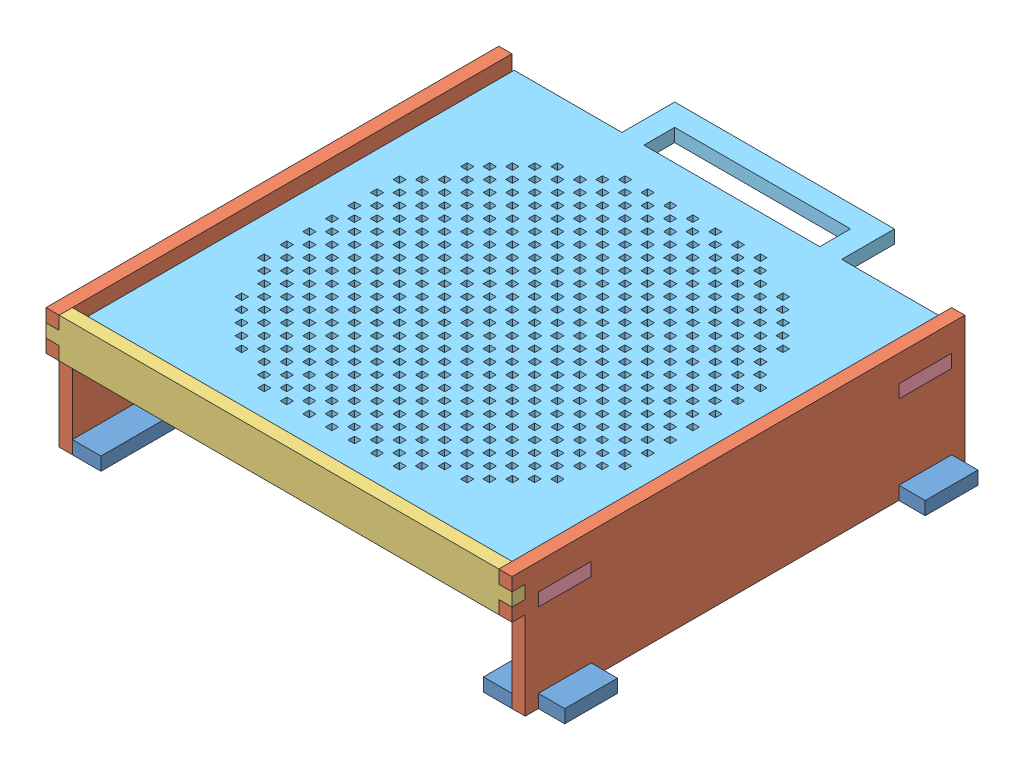
SolidWorks assembly Cama de impresión acrílico, configuration Predeterminado. Lengths in mm.
Overall size (112 29 115).
7 component instances, 5 part files, 18 mates.
Components (placement in the parent):
- Sosten Petri-2: Sosten Petri [Predeterminado] at (44.331 48.7643 99.392) x (-1 0 0) z (0 1 0) size (112 106 3)
- Pared lateral_Cama de impresión-1: Pared lateral_Cama de impresión [Predeterminado] at (94.331 48.7643 149.392) x (0 0 -1) z (1 0 0) size (103 29 3)
- Pared lateral_Cama de impresión-2: Pared lateral_Cama de impresión [Predeterminado] at (-8.669 48.7643 149.392) x (0 0 -1) z (1 0 0) size (103 29 3)
- Cara trasera cama-1: Cara trasera cama [Predeterminado] at (-5.669 68.7643 149.392) size (106 9 3)
- Soporte placa-1: Soporte placa [Predeterminado] at (94.331 68.7643 49.392) x (-1 0 0) z (0 1 0) size (7 100 3)
- Soporte placa-4: Soporte placa [Predeterminado] at (-5.669 68.7643 149.392) x (1 0 0) z (0 1 0) size (7 100 3)
- Cama impresion mock-2: Cama impresion mock [Predeterminado] at (-5.169 74.7643 49.392) x (1 0 0) z (0 -1 0) size (99 112 3)
Mates (geometry in assembly coordinates):
- Coincidente1: coincident anti-aligned: plane of Sosten Petri-2 through (-5.669 51.7643 49.392) normal (-1 0 0); plane of Pared lateral_Cama de impresión-2 through (-5.669 48.7643 149.392) normal (1 0 0)
- Coincidente2: coincident anti-aligned: plane of Sosten Petri-2 through (44.331 51.7643 99.392) normal (0 1 0); plane of Pared lateral_Cama de impresión-2 through (-5.669 51.7643 146.392) normal (0 -1 0)
- Coincidente3: coincident anti-aligned: plane of Sosten Petri-2 through (-5.669 48.7643 134.392) normal (0 0 -1); plane of Pared lateral_Cama de impresión-2 through (-5.669 48.7643 134.392) normal (0 0 1)
- Coincidente4: coincident anti-aligned: plane of Sosten Petri-2 through (94.331 51.7643 49.392) normal (1 0 0); plane of Pared lateral_Cama de impresión-1 through (94.331 48.7643 149.392) normal (-1 0 0)
- Coincidente5: coincident anti-aligned: plane of Sosten Petri-2 through (44.331 51.7643 99.392) normal (0 1 0); plane of Pared lateral_Cama de impresión-1 through (97.331 51.7643 146.392) normal (0 -1 0)
- Coincidente6: coincident anti-aligned: plane of Sosten Petri-2 through (94.331 48.7643 146.392) normal (0 0 1); plane of Pared lateral_Cama de impresión-1 through (97.331 48.7643 146.392) normal (0 0 -1)
- Coincidente8: coincident anti-aligned: plane of Pared lateral_Cama de impresión-2 through (-5.669 48.7643 149.392) normal (0 0 1); plane of Cara trasera cama-1 through (-5.669 68.7643 149.392) normal (0 0 -1)
- Coincidente10: coincident aligned: plane of Pared lateral_Cama de impresión-1 through (97.331 48.7643 149.392) normal (1 0 0); plane of Cara trasera cama-1 through (97.331 74.7643 152.392) normal (1 0 0)
- Coincidente13: coincident anti-aligned: plane of Pared lateral_Cama de impresión-2 through (-5.669 48.7643 149.392) normal (1 0 0); plane of Soporte placa-4 through (-5.669 71.7643 134.392) normal (-1 0 0)
- Coincidente14: coincident anti-aligned: plane of Pared lateral_Cama de impresión-2 through (-5.669 71.7643 52.392) normal (0 0 1); plane of Soporte placa-4 through (-5.669 71.7643 52.392) normal (0 0 -1)
- Coincidente15: coincident anti-aligned: plane of Pared lateral_Cama de impresión-2 through (-5.669 71.7643 64.392) normal (0 -1 0); plane of Soporte placa-4 through (-5.669 71.7643 149.392) normal (0 1 0)
- Coincidente21: coincident anti-aligned: plane of Pared lateral_Cama de impresión-1 through (94.331 48.7643 149.392) normal (-1 0 0); plane of Soporte placa-1 through (94.331 71.7643 64.392) normal (1 0 0)
- Coincidente22: coincident anti-aligned: plane of Pared lateral_Cama de impresión-1 through (97.331 71.7643 64.392) normal (0 -1 0); plane of Soporte placa-1 through (94.331 71.7643 49.392) normal (0 1 0)
- Coincidente24: coincident aligned: plane of Pared lateral_Cama de impresión-1 through (97.331 48.7643 49.392) normal (0 0 -1); plane of Soporte placa-1 through (94.331 71.7643 49.392) normal (0 0 -1)
- Coincidente28: coincident anti-aligned: plane of Soporte placa-4 through (-5.669 71.7643 149.392) normal (0 1 0); plane of Cama impresion mock-2 through (-5.169 71.7643 49.392) normal (0 -1 0)
- Distancia1: distance = 0.5 mm anti-aligned: plane of Cama impresion mock-2 through (93.831 71.7643 149.392) normal (1 0 0); plane of Pared lateral_Cama de impresión-1 through (94.331 48.7643 149.392) normal (-1 0 0)
- Distancia límite1: limit distance = 0 mm anti-aligned: plane of Cara trasera cama-1 through (-5.669 68.7643 149.392) normal (0 0 -1); plane of Cama impresion mock-2 through (-5.169 71.7643 149.392) normal (0 0 1)
- Coincidente29: coincident anti-aligned: plane of Pared lateral_Cama de impresión-1 through (94.331 71.7643 149.392) normal (0 1 0); plane of Cara trasera cama-1 through (94.331 71.7643 152.392) normal (0 -1 0)
